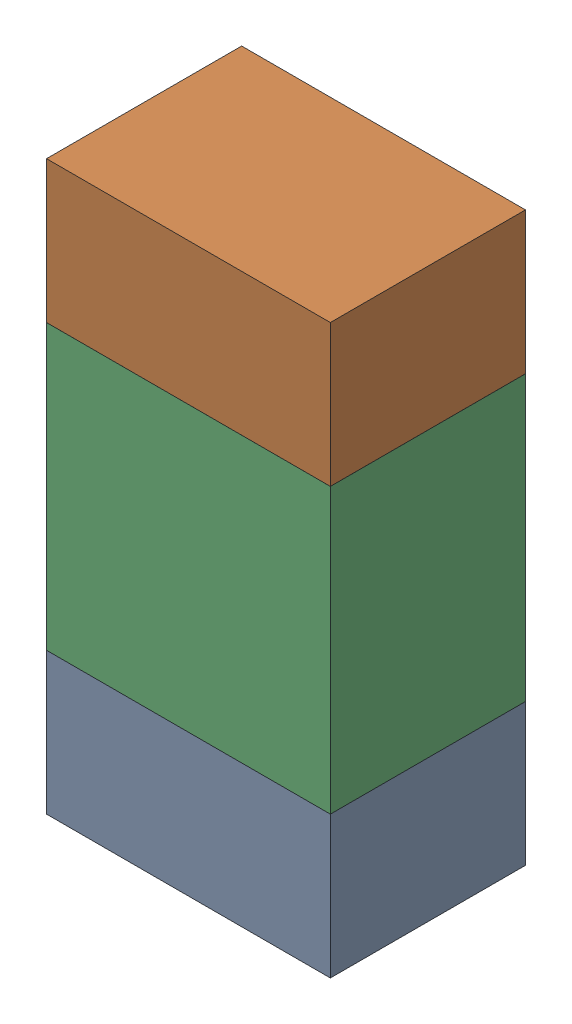
SolidWorks assembly R50, configuration ﾃﾞﾌｫﾙﾄ. Lengths in mm.
Overall size (0.8 1.6 0.55).
6 component instances, 2 part files, 0 mates.
Components (placement in the parent):
- 689261784-1: 689261784 [ﾃﾞﾌｫﾙﾄ] at (34.6076 15.2751 -1.7503) size (0.8 0.4 0.55)
  - Extruded_34-1: Extruded_34 [ﾃﾞﾌｫﾙﾄ] at origin size (0.8 0.4 0.55)
- 689261784-2: 689261784 [ﾃﾞﾌｫﾙﾄ] at (34.6076 16.4751 -1.7503) size (0.8 0.4 0.55)
  - Extruded_34-1: Extruded_34 [ﾃﾞﾌｫﾙﾄ] at origin size (0.8 0.4 0.55)
- 689261648-1: 689261648 [ﾃﾞﾌｫﾙﾄ] at (34.6076 15.875 -1.7503) size (0.8 0.8 0.55)
  - Extruded_33-1: Extruded_33 [ﾃﾞﾌｫﾙﾄ] at origin size (0.8 0.8 0.55)
